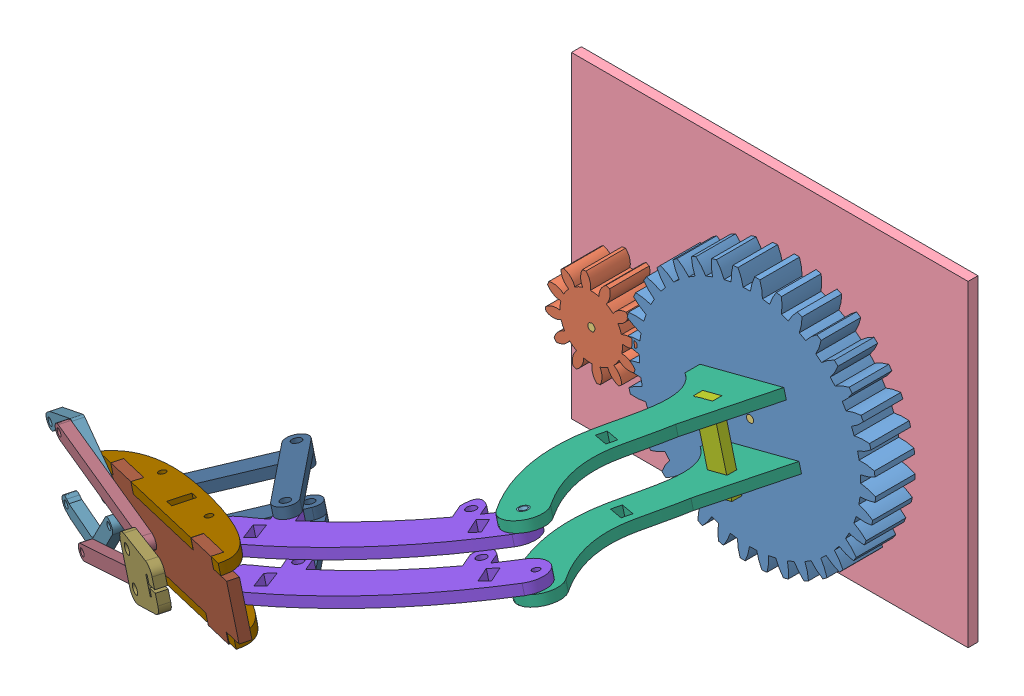
SolidWorks assembly Arm, configuration Default. Lengths in mm.
Overall size (373.12 213.16 308.31).
26 component instances, 14 part files, 70 mates.
Components (placement in the parent):
- BIGGEARGOODCOPY-1: BIGGEARGOODCOPY [Default] at (96.3661 -42.0789 -20.182) x (0.967952 0.251134 0) z (0 0 1) size (160.85 160.85 25.4)
- SMALLGEARGOODCOPY-1: SMALLGEARGOODCOPY [Default] at (-100.0688 -78.533 -20.182) x (0.933414 0.3588 0) z (0 0 1) size (58.38 58.38 25.4)
- playAxel-3: playAxel [Default] at (-5.2339 -42.0789 5.218) x (0.687394 0.726285 0) z (-0.726285 0.687394 0) size (4.76 50.8 4.76)
- playAxel-4: playAxel [Default] at (96.3661 -42.0789 5.218) x (0.965033 0.262129 0) z (-0.262129 0.965033 0) size (4.76 50.8 4.76)
- Base-1: Base [Default] at (64.6161 -42.0789 -45.582) x (1 0 0) z (0 -1 0) size (254 6.35 203.2)
- BronzeSleeveBearing-1: BronzeSleeveBearing [Default] at (-5.2339 -42.0789 -39.232) x (1 0 0) z (0 1 0) size (6.35 6.35 6.35)
- BronzeSleeveBearing-2: BronzeSleeveBearing [Default] at (96.3661 -42.0789 -45.582) x (1 0 0) z (0 -1 0) size (6.35 6.35 6.35)
- arm_base (1)-1: arm_base (1) [Default] at (74.0874 -63.8923 5.218) x (0.967952 0.251134 0) z (0.251134 -0.967952 0) size (63.12 163.71 6.35)
- arm_base (1)-3: arm_base (1) [Default] at (64.3536 -27.791 5.218) x (0.967952 0.251134 0) z (0.251134 -0.967952 0) size (63.12 163.71 6.35)
- slot-arm-1: slot-arm [Default] at (97.6763 -45.3865 24.2567) x (-0.251134 0.967952 0) z (0.967952 0.251134 0) size (50.8 6.35 12.7)
- Kd-long-slot-1: Kd-long-slot [Default] at (83.2804 -61.5072 179.9492) x (-0.92892 -0.241007 -0.281112) z (-0.251134 0.967952 0) size (126.68 122.94 6.35)
- Kd-long-slot-2: Kd-long-slot [Default] at (76.8173 -37.6778 180.0134) x (-0.929675 -0.241203 -0.278434) z (-0.251134 0.967952 0) size (126.68 122.94 6.35)
- BronzeSleeveBearing-3: BronzeSleeveBearing [Default] at (105.6233 -55.7104 149.8814) x (-0.198204 -0.051424 0.978811) z (0.947442 0.245813 0.204766) size (6.35 6.35 6.35)
- BronzeSleeveBearing-4: BronzeSleeveBearing [Default] at (95.8895 -19.6091 149.8814) x (-0.248085 -0.064365 0.966598) z (0.93562 0.242745 0.256299) size (6.35 6.35 6.35)
- arm_head-5: arm_head [Default] at (-112.5015 -112.3025 173.6792) x (0.892226 0.231487 0.387746) z (0.251134 -0.967952 0) size (152.82 23.87 6.35)
- arm_head-6: arm_head [Default] at (-122.0441 -76.1517 174.055) x (0.892226 0.231487 0.387746) z (0.251134 -0.967952 0) size (152.82 23.87 6.35)
- kd-short-arm-slot-5: kd-short-arm-slot [Default] at (-52.91 -58.2149 146.3127) x (-0.637313 -0.16535 -0.752656) z (-0.728535 -0.189018 0.658414) size (76.2 6.35 13.53)
- kd-short-arm-slot-6: kd-short-arm-slot [Default] at (-85.8185 -73.3132 197.8575) x (-0.550558 -0.142842 0.822485) z (0.796127 0.206554 0.568786) size (76.2 6.35 13.53)
- kd-short-arm-slot-7: kd-short-arm-slot [Default] at (-43.2879 -94.3452 145.9938) x (-0.637224 -0.165327 -0.752737) z (-0.728613 -0.189038 0.658322) size (76.2 6.35 13.53)
- kd-short-arm-slot-8: kd-short-arm-slot [Default] at (-79.4653 -97.1711 197.4817) x (-0.551826 -0.143171 0.821578) z (0.795248 0.206326 0.570097) size (76.2 6.35 13.53)
- arm_head_top-3: arm_head_top [Default] at (21.4665 -78.2795 257.479) x (-0.892226 -0.231487 -0.387746) z (0.251134 -0.967952 0) size (152.4 6.35 44.45)
- armGrasperSyringeConnector-1: armGrasperSyringeConnector [Default] at (-68.5344 -87.0992 240.568) x (-0.251134 0.967952 0) z (-0.892226 -0.231487 -0.387746) size (36.4 6.35 38.1)
- armGrasperMiddleConnector-1: armGrasperMiddleConnector [Default] at (-153.2122 -69.2576 201.0853) x (0.926549 -0.012206 0.375977) z (-0.02536 0.995173 0.094805) size (102.87 6.35 8.89)
- armGrasperMiddleConnector-2: armGrasperMiddleConnector [Default] at (-52.5931 -88.0736 233.1781) x (-0.827683 -0.412432 -0.38058) z (-0.417225 0.905769 -0.074197) size (102.87 6.35 8.89)
- arm_grabby_bit-1: arm_grabby_bit [Default] at (-112.4321 -105.0184 207.0232) x (-0.54723 -0.779373 -0.305151) z (0.748114 -0.618948 0.239226) size (63.29 6.35 36.98)
- arm_grabby_bit-2: arm_grabby_bit [Default] at (-114.1325 -88.6601 201.1699) x (-0.838583 0.459318 -0.292926) z (0.39486 0.882919 0.254049) size (63.29 6.35 36.98)
Mates (geometry in assembly coordinates):
- Parallel2: parallel aligned: plane of BIGGEARGOODCOPY-1 through (129.0119 -24.9074 5.218) normal (0 0 1); plane of SMALLGEARGOODCOPY-1 through (0.0447 -53.1836 5.218) normal (0 0 1)
- Concentric4: concentric anti-aligned: circle of SMALLGEARGOODCOPY-1; circle of playAxel-3
- Coincident5: coincident aligned: plane of SMALLGEARGOODCOPY-1 through (0.0447 -53.1836 5.218) normal (0 0 1); plane of playAxel-3 through (-5.2339 -42.0789 5.218) normal (0 0 1)
- Concentric5: concentric anti-aligned: circle of BIGGEARGOODCOPY-1; circle of playAxel-4
- Coincident6: coincident aligned: plane of BIGGEARGOODCOPY-1 through (129.0119 -24.9074 5.218) normal (0 0 1); plane of playAxel-4 through (96.3661 -42.0789 5.218) normal (0 0 1)
- Coincident7: coincident aligned: plane of BIGGEARGOODCOPY-1 through (129.0119 -24.9074 5.218) normal (0 0 1); plane of SMALLGEARGOODCOPY-1 through (0.0447 -53.1836 5.218) normal (0 0 1)
- Concentric6: concentric anti-aligned: cylinder of Base-1 through (96.3661 -42.0789 -39.232) axis (0 0 -1) radius 3.048; circle of BronzeSleeveBearing-2
- Coincident9: coincident aligned: plane of Base-1 through (64.6161 -42.0789 -39.232) normal (0 0 1); plane of BronzeSleeveBearing-2 through (96.3661 -42.0789 -39.232) normal (0 0 1)
- Concentric7: concentric anti-aligned: circle of Base-1; circle of BronzeSleeveBearing-1
- Coincident11: coincident aligned: plane of Base-1 through (64.6161 -42.0789 -39.232) normal (0 0 1); plane of BronzeSleeveBearing-1 through (-5.2339 -42.0789 -39.232) normal (0 0 1)
- Concentric8: concentric anti-aligned: circle of playAxel-3; cylinder of BronzeSleeveBearing-1 through (-5.2339 -42.0789 -45.582) axis (0 0 1) radius 2.3813
- Concentric9: concentric anti-aligned: circle of playAxel-4; circle of BronzeSleeveBearing-2
- Coincident14: coincident aligned: plane of playAxel-3 through (-5.2339 -42.0789 -45.582) normal (0 0 -1); plane of Base-1 through (64.6161 -42.0789 -45.582) normal (0 0 -1)
- Coincident15: coincident anti-aligned: plane of BIGGEARGOODCOPY-1 through (101.8583 -63.2474 -20.182) normal (-0.251134 0.967952 0); plane of arm_base (1)-1 through (99.8908 -63.7579 89.7717) normal (0.251134 -0.967952 0)
- Coincident16: coincident anti-aligned: plane of BIGGEARGOODCOPY-1 through (78.0987 -46.8183 -20.182) normal (0.967952 0.251134 0); plane of arm_base (1)-1 through (83.5909 -67.9869 5.218) normal (-0.967952 -0.251134 0)
- Coincident19: coincident anti-aligned: plane of BIGGEARGOODCOPY-1 through (129.0119 -24.9074 5.218) normal (0 0 1); plane of arm_base (1)-1 through (75.6821 -70.0388 5.218) normal (0 0 -1)
- Coincident25: coincident anti-aligned: plane of BIGGEARGOODCOPY-1 through (114.6335 -37.3394 -20.182) normal (-0.967952 -0.251134 0); plane of arm_base (1)-3 through (110.7361 -22.3174 -1.132) normal (0.967952 0.251134 0)
- Coincident26: coincident anti-aligned: plane of BIGGEARGOODCOPY-1 through (90.874 -20.9103 -20.182) normal (0.251134 -0.967952 0); plane of arm_base (1)-3 through (88.5623 -21.5101 89.7717) normal (-0.251134 0.967952 0)
- Coincident27: coincident anti-aligned: plane of BIGGEARGOODCOPY-1 through (129.0119 -24.9074 5.218) normal (0 0 1); plane of arm_base (1)-3 through (65.9483 -33.9375 5.218) normal (0 0 -1)
- Coincident28: coincident anti-aligned: plane of arm_base (1)-1 through (96.8237 -64.5536 24.2567) normal (0 0 1); plane of slot-arm-1 through (97.6763 -45.3865 24.2567) normal (0 0 -1)
- Coincident29: coincident aligned: plane of arm_base (1)-3 through (88.5623 -21.5101 89.7717) normal (-0.251134 0.967952 0); plane of slot-arm-1 through (85.151 -22.3952 30.6067) normal (-0.251134 0.967952 0)
- Coincident30: coincident anti-aligned: plane of arm_base (1)-3 through (99.0387 -25.3523 30.2511) normal (-0.967952 -0.251134 0); plane of slot-arm-1 through (110.2016 -68.3777 30.6067) normal (0.967952 0.251134 0)
- Concentric10: concentric anti-aligned: circle of arm_base (1)-1; circle of Kd-long-slot-1
- Coincident32: coincident anti-aligned: plane of arm_base (1)-1 through (98.2961 -57.6114 89.7717) normal (-0.251134 0.967952 0); plane of Kd-long-slot-1 through (83.2804 -61.5072 179.9492) normal (0.251134 -0.967952 0)
- Concentric12: concentric anti-aligned: circle of arm_base (1)-3; circle of Kd-long-slot-2
- Coincident33: coincident anti-aligned: plane of arm_base (1)-3 through (90.157 -27.6566 89.7717) normal (0.251134 -0.967952 0); plane of Kd-long-slot-2 through (75.2226 -31.5313 180.0134) normal (-0.251134 0.967952 0)
- Concentric17: concentric aligned: circle of arm_base (1)-1; circle of BronzeSleeveBearing-3
- Coincident36: coincident aligned: plane of arm_base (1)-1 through (99.8908 -63.7579 89.7717) normal (0.251134 -0.967952 0); plane of BronzeSleeveBearing-3 through (107.218 -61.8568 149.8814) normal (0.251134 -0.967952 0)
- Concentric18: concentric aligned: circle of arm_base (1)-3; circle of BronzeSleeveBearing-4
- Coincident37: coincident aligned: plane of arm_base (1)-3 through (88.5623 -21.5101 89.7717) normal (-0.251134 0.967952 0); plane of BronzeSleeveBearing-4 through (95.8895 -19.6091 149.8814) normal (-0.251134 0.967952 0)
- Parallel5: parallel aligned: face of Kd-long-slot-1; face of Kd-long-slot-2
- Coincident63: coincident anti-aligned: plane of Kd-long-slot-1 through (83.2804 -61.5072 179.9492) normal (0.251134 -0.967952 0); plane of arm_head-5 through (-21.5514 -88.7056 214.1528) normal (-0.251134 0.967952 0)
- Concentric34: concentric anti-aligned: circle of Kd-long-slot-1; circle of arm_head-5
- Coincident65: coincident anti-aligned: plane of Kd-long-slot-2 through (75.2226 -31.5313 180.0134) normal (-0.251134 0.967952 0); plane of arm_head-6 through (-29.4993 -58.7013 214.5285) normal (0.251134 -0.967952 0)
- Concentric35: concentric anti-aligned: circle of Kd-long-slot-2; circle of arm_head-6
- Parallel9: parallel aligned: plane of arm_head-5 through (-103.0777 -116.4178 195.4076) normal (-0.375319 -0.097376 0.921766); plane of arm_head-6 through (-112.6203 -80.2669 195.7834) normal (-0.375319 -0.097376 0.921766)
- Parallel10: parallel aligned: plane of arm_head-5 through (-12.4275 -92.8987 234.8026) normal (-0.375319 -0.097376 0.921766); plane of arm_head-6 through (-21.9701 -56.7478 235.1783) normal (-0.375319 -0.097376 0.921766)
- Parallel11: parallel aligned: plane of arm_head-5 through (-82.7984 -111.1563 211.1096) normal (-0.375319 -0.097376 0.921766); plane of arm_head-6 through (-92.341 -75.0055 211.4854) normal (-0.375319 -0.097376 0.921766)
- Coincident81: coincident anti-aligned: plane of Kd-long-slot-2 through (75.2226 -31.5313 180.0134) normal (-0.251134 0.967952 0); plane of kd-short-arm-slot-5 through (-51.3153 -64.3614 146.3127) normal (0.251134 -0.967952 0)
- Concentric36: concentric anti-aligned: circle of Kd-long-slot-2; circle of kd-short-arm-slot-5
- Coincident82: coincident anti-aligned: plane of kd-short-arm-slot-5 through (-51.3153 -64.3614 146.3127) normal (0.251134 -0.967952 0); plane of kd-short-arm-slot-6 through (-85.8185 -73.3132 197.8575) normal (-0.251134 0.967952 0)
- Concentric37: concentric aligned: circle of kd-short-arm-slot-5; circle of kd-short-arm-slot-6
- Coincident88: coincident anti-aligned: plane of arm_head-6 through (-29.4993 -58.7013 214.5285) normal (0.251134 -0.967952 0); plane of kd-short-arm-slot-6 through (-85.8185 -73.3132 197.8575) normal (-0.251134 0.967952 0)
- Concentric38: concentric aligned: circle of arm_head-6; circle of kd-short-arm-slot-6
- Coincident89: coincident anti-aligned: plane of Kd-long-slot-1 through (83.2804 -61.5072 179.9492) normal (0.251134 -0.967952 0); plane of kd-short-arm-slot-7 through (-43.2879 -94.3452 145.9938) normal (-0.251134 0.967952 0)
- Concentric39: concentric anti-aligned: circle of Kd-long-slot-1; circle of kd-short-arm-slot-7
- Coincident90: coincident anti-aligned: plane of kd-short-arm-slot-7 through (-43.2879 -94.3452 145.9938) normal (-0.251134 0.967952 0); plane of kd-short-arm-slot-8 through (-77.8706 -103.3176 197.4817) normal (0.251134 -0.967952 0)
- Concentric40: concentric aligned: circle of kd-short-arm-slot-7; circle of kd-short-arm-slot-8
- Coincident92: coincident anti-aligned: plane of arm_head-5 through (-21.5514 -88.7056 214.1528) normal (-0.251134 0.967952 0); plane of kd-short-arm-slot-8 through (-77.8706 -103.3176 197.4817) normal (0.251134 -0.967952 0)
- Concentric41: concentric aligned: circle of arm_head-5; circle of kd-short-arm-slot-8
- Coincident97: coincident anti-aligned: plane of arm_head-6 through (-112.6203 -80.2669 195.7834) normal (-0.375319 -0.097376 0.921766); plane of arm_head_top-3 through (23.8498 -77.6611 251.6257) normal (0.375319 0.097376 -0.921766)
- Coincident98: coincident anti-aligned: plane of arm_head-6 through (-115.0036 -80.8852 201.6366) normal (0.892226 0.231487 0.387746); plane of arm_head_top-3 through (-112.6203 -80.2669 195.7834) normal (-0.892226 -0.231487 -0.387746)
- Parallel16: parallel anti-aligned: plane of arm_head-6 through (-92.341 -75.0055 211.4854) normal (-0.892226 -0.231487 -0.387746); plane of arm_head_top-3 through (-89.7311 -74.3283 205.7306) normal (0.892226 0.231487 0.387746)
- Coincident101: coincident anti-aligned: plane of arm_head-5 through (-105.461 -117.0361 201.2608) normal (0.892226 0.231487 0.387746); plane of arm_head_top-3 through (-104.6468 -110.9994 195.7834) normal (-0.892226 -0.231487 -0.387746)
- Parallel18: parallel anti-aligned: plane of arm_head-5 through (7.8517 -87.6373 250.5045) normal (-0.892226 -0.231487 -0.387746); plane of arm_head_top-3 through (9.1192 -81.483 245.2241) normal (0.892226 0.231487 0.387746)
- Coincident104: coincident anti-aligned: plane of arm_head-6 through (-29.4993 -58.7013 214.5285) normal (0.251134 -0.967952 0); plane of arm_head_top-3 through (-21.7435 -56.689 235.2768) normal (-0.251134 0.967952 0)
- Coincident116: coincident anti-aligned: plane of arm_head_top-3 through (21.4665 -78.2795 257.479) normal (-0.375319 -0.097376 0.921766); plane of arm_grabby_bit-1 through (-110.0488 -104.4001 201.1699) normal (0.375319 0.097376 -0.921766)
- Concentric48: concentric aligned: circle of arm_head_top-3; circle of arm_grabby_bit-1
- Coincident118: coincident anti-aligned: plane of arm_grabby_bit-2 through (-114.1325 -88.6601 201.1699) normal (0.375319 0.097376 -0.921766); plane of arm_head_top-3 through (21.4665 -78.2795 257.479) normal (-0.375319 -0.097376 0.921766)
- Concentric49: concentric anti-aligned: circle of arm_head_top-3; circle of arm_grabby_bit-2
- Coincident120: coincident anti-aligned: plane of armGrasperMiddleConnector-1 through (-146.5977 -73.1171 196.4819) normal (0.375319 0.097376 -0.921766); plane of arm_grabby_bit-2 through (-116.5158 -89.2784 207.0232) normal (-0.375319 -0.097376 0.921766)
- Concentric50: concentric anti-aligned: circle of armGrasperMiddleConnector-1; circle of arm_grabby_bit-2
- Coincident122: coincident anti-aligned: plane of armGrasperMiddleConnector-2 through (-54.4176 -93.933 231.8162) normal (0.375319 0.097376 -0.921766); plane of arm_grabby_bit-1 through (-112.4321 -105.0184 207.0232) normal (-0.375319 -0.097376 0.921766)
- Concentric51: concentric anti-aligned: circle of armGrasperMiddleConnector-2; circle of arm_grabby_bit-1
- Parallel20: parallel aligned: line of arm_head_top-3 through (-16.1533 -88.0399 241.1301) axis (-0.892226 -0.231487 -0.387746); line of armGrasperSyringeConnector-1 through (-34.3174 -79.1401 255.3411) axis (-0.892226 -0.231487 -0.387746)
- Parallel23: parallel anti-aligned: plane of arm_head_top-3 through (21.4665 -78.2795 257.479) normal (-0.375319 -0.097376 0.921766); plane of armGrasperSyringeConnector-1 through (-57.5095 -96.4816 237.177) normal (0.375319 0.097376 -0.921766)
- Distance2: distance = 12.7 mm anti-aligned: plane of armGrasperSyringeConnector-1 through (-57.5095 -96.4816 237.177) normal (0.375319 0.097376 -0.921766); plane of arm_head_top-3 through (21.4665 -78.2795 257.479) normal (-0.375319 -0.097376 0.921766)
- Distance4: distance = 50.8 mm aligned: plane of arm_head_top-3 through (15.8763 -46.9286 251.6257) normal (0.892226 0.231487 0.387746); plane of armGrasperSyringeConnector-1 through (-34.0086 -70.5258 249.4879) normal (0.892226 0.231487 0.387746)
- Concentric54: concentric anti-aligned: circle of armGrasperSyringeConnector-1; circle of armGrasperMiddleConnector-2
- Concentric55: concentric aligned: circle of armGrasperSyringeConnector-1; circle of armGrasperMiddleConnector-1
